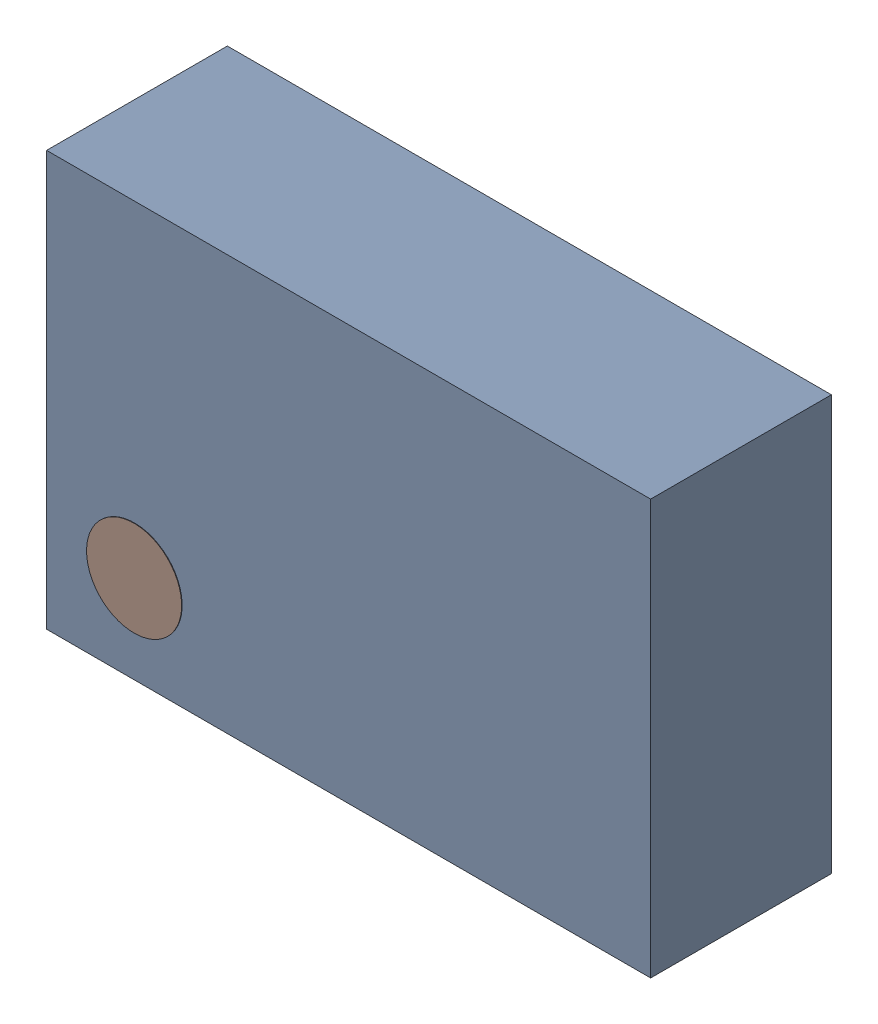
SolidWorks assembly User Library-dsbga_12_Free-Models, configuration Default. Lengths in mm.
Overall size (1.27 0.87 0.55).
16 component instances, 3 part files, 0 mates.
Components (placement in the parent):
- User Library-dsbga_12_582294864-1: User Library-dsbga_12_582294864 [Default] at (0.0001 0.0001 0.17) size (1.27 0.87 0.38)
  - User Library-dsbga_12_Extruded-1: User Library-dsbga_12_Extruded [Default] at origin size (1.27 0.87 0.38)
- User Library-dsbga_12_582411960-1: User Library-dsbga_12_582411960 [Default] at (-0.3999 0.2001 0.125) size (0.24 0.24 0.24)
  - User Library-dsbga_12_Sphere-1: User Library-dsbga_12_Sphere [Default] at origin size (0.24 0.24 0.24)
- User Library-dsbga_12_582411960-2: User Library-dsbga_12_582411960 [Default] at (0.0001 0.2001 0.125) size (0.24 0.24 0.24)
  - User Library-dsbga_12_Sphere-1: User Library-dsbga_12_Sphere [Default] at origin size (0.24 0.24 0.24)
- User Library-dsbga_12_582411960-3: User Library-dsbga_12_582411960 [Default] at (0.4001 0.2001 0.125) size (0.24 0.24 0.24)
  - User Library-dsbga_12_Sphere-1: User Library-dsbga_12_Sphere [Default] at origin size (0.24 0.24 0.24)
- User Library-dsbga_12_582411960-4: User Library-dsbga_12_582411960 [Default] at (0.4001 -0.1999 0.125) size (0.24 0.24 0.24)
  - User Library-dsbga_12_Sphere-1: User Library-dsbga_12_Sphere [Default] at origin size (0.24 0.24 0.24)
- User Library-dsbga_12_582411960-5: User Library-dsbga_12_582411960 [Default] at (0.0001 -0.1999 0.125) size (0.24 0.24 0.24)
  - User Library-dsbga_12_Sphere-1: User Library-dsbga_12_Sphere [Default] at origin size (0.24 0.24 0.24)
- User Library-dsbga_12_582411960-6: User Library-dsbga_12_582411960 [Default] at (-0.3999 -0.1999 0.125) size (0.24 0.24 0.24)
  - User Library-dsbga_12_Sphere-1: User Library-dsbga_12_Sphere [Default] at origin size (0.24 0.24 0.24)
- User Library-dsbga_12_582412080-1: User Library-dsbga_12_582412080 [Default] at (-0.4499 -0.2499 0.2) size (0.2 0.2 0.35)
  - User Library-dsbga_12_Cylinder-1: User Library-dsbga_12_Cylinder [Default] at origin size (0.2 0.2 0.35)
